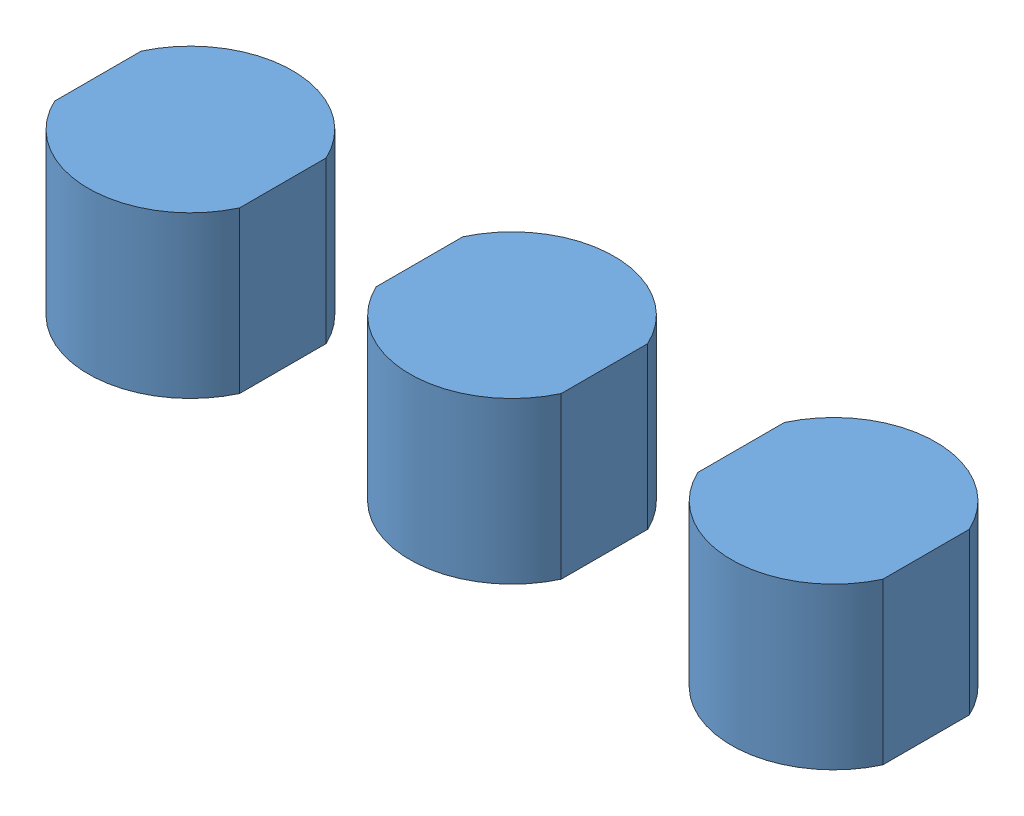
SolidWorks assembly barrel assem, configuration Default. Lengths in mm.
Overall size (51.5 10 12.7).
3 component instances, 1 part files, 8 mates.
Components (placement in the parent):
- barrel-1: barrel [Default] at origin size (11.5 10 12.7)
- barrel-2: barrel [Default] at (20 0 0) size (11.5 10 12.7)
- barrel-3: barrel [Default] at (-20 0 0) size (11.5 10 12.7)
Mates (geometry in assembly coordinates):
- Distance7: distance = 0 mm: plane of barrel-2 through (20 0 0) normal (0 -1 0); plane of barrel-1 through (0 0 0) normal (0 -1 0)
- Distance2: distance = 0 mm: plane of barrel-3 through (-20 0 0) normal (0 -1 0); plane of barrel-1 through (0 0 0) normal (0 -1 0)
- Parallel8: parallel: plane of barrel-1 through (5.7521 10 0) normal (1 0 0); plane of barrel-2 through (13.6706 10 -18.3657) normal (1 0 0)
- Parallel9: parallel: plane of barrel-1 through (-5.7521 10 0) normal (-1 0 0); plane of barrel-3 through (-24.1799 10 -7.7728) normal (-1 0 0)
- Distance10: distance = 20 mm: line of barrel-1 through (5.7521 10 -2.69) axis (0 -1 0); line of barrel-2 through (25.7521 10 -2.69) axis (0 -1 0)
- Distance11: distance = 20 mm: line of barrel-1 through (-5.7521 10 -2.69) axis (0 -1 0); line of barrel-3 through (-25.7521 10 -2.69) axis (0 -1 0)
- Distance15: distance = 20 mm aligned: plane of barrel-3 through (-14.2479 10 0) normal (1 0 0); plane of barrel-1 through (5.7521 10 0) normal (1 0 0)
- Distance16: distance = 20 mm aligned: plane of barrel-2 through (14.2479 10 0) normal (-1 0 0); plane of barrel-1 through (-5.7521 10 0) normal (-1 0 0)
